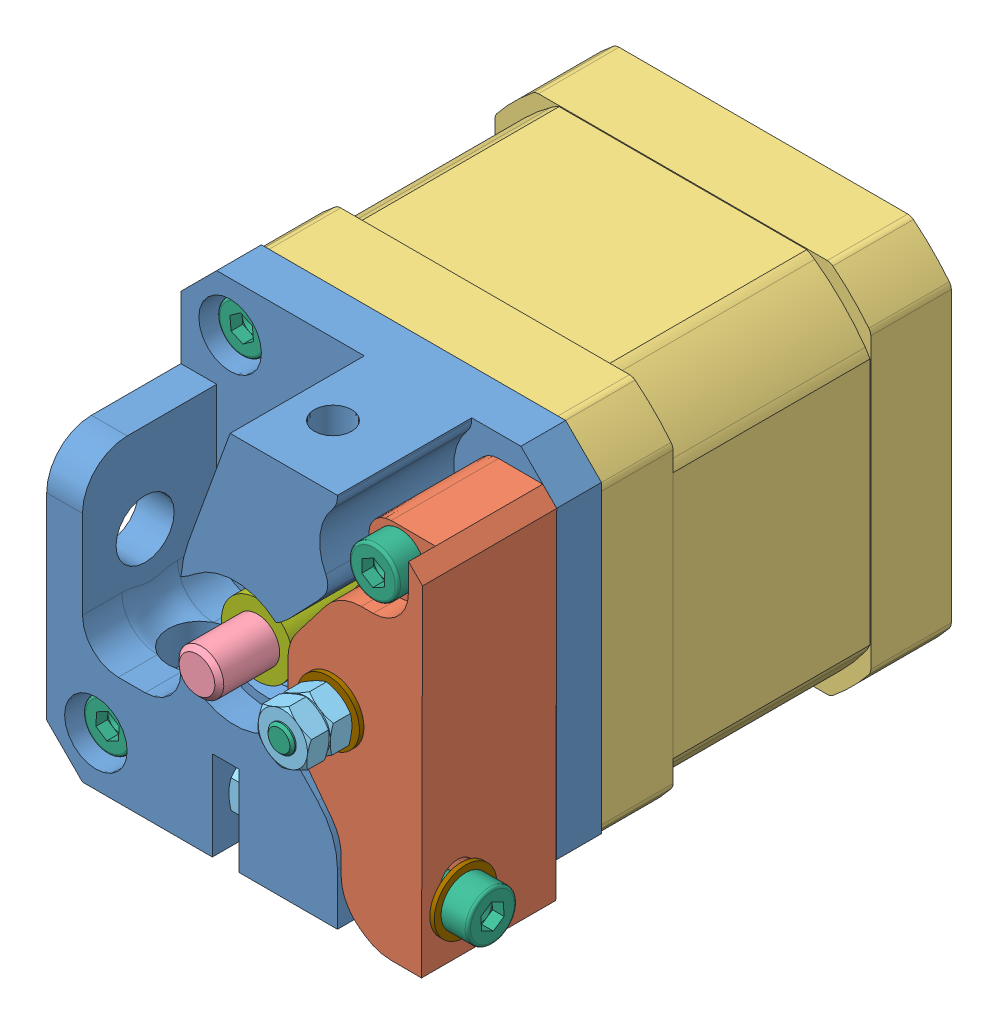
SolidWorks assembly ExtruderDD1, configuration Default. Lengths in mm.
Overall size (45.82 42.02 65.09).
19 component instances, 9 part files, 27 mates.
Components (placement in the parent):
- DD-1 extruder-1: DD-1 extruder [Default] at origin size (42 42 20)
- DD-1 Idler-1: DD-1 Idler [Default] at (21.0104 18.9837 0) x (0.002967 0.999996 0) z (0 0 1) size (39.57 15 15)
- Stepper_motor_NEMA17 39mm-1: Stepper_motor_NEMA17 39mm [Default] at (0 0 -18) x (1 0 0) z (0 -1 0) size (42 63.3 42)
  - Stator-1: Stator [Default] at origin size (42 41.1 42)
  - Rotor-1: Rotor [Default] x (0.508449 0 0.861092) z (-0.861092 0 0.508449) size (21 60.8 21)
- Hex nut-1: Hex nut [M3 Hex Nut] at (-1.8851 -15.1119 -4) x (0 0 1) z (-1 0 0) size (5.5 6.35 2.4)
- Socket head cap screw-1: Socket head cap screw [M3x10] at (-15.5 15.5 -16.3) x (0 0 -1) z (0.417389 0.908728 0) size (13 5.5 5.5)
- Socket head cap screw-3: Socket head cap screw [M3x25] at (24.8182 -15.1119 -4) x (-1 0 0) z (0 0.898586 -0.438797) size (28 5.5 5.5)
- Socket head cap screw-5: Socket head cap screw [M3x20] at (-15.5 -15.5 -1.3) x (0 0 -1) z (0.998489 -0.054943 0) size (23 5.5 5.5)
- Socket head cap screw-7: Socket head cap screw [M3x20] at (15.5 15.5 0) x (0 0 -1) z (-0.467841 0.883812 0) size (23 5.5 5.5)
- MK8 hobbed gear-1: MK8 hobbed gear [Default] at (0 0 -2.5414) x (0.957517 0.288377 0) z (0 0 1) size (8 8 13)
- 4mm Bearing SKF 624 RS 286-7798-1: 4mm Bearing SKF 624 RS 286-7798 [Default] at (10.954 0.0134 -9.5568) x (0 0 -1) z (0.991845 -0.127452 0) size (5 13 13)
- Socket head cap screw-8: Socket head cap screw [M3x16] at (10.954 0.0134 -13.0115) x (0 0 1) z (-0.999739 -0.022865 0) size (19 5.5 5.5)
- Plain washer-1: Plain washer [M3 plain washer] at (10.954 0.0134 -10.0115) x (0 0 -1) z (0.919176 0.393848 0) size (0.5 7 7)
- Plain washer-2: Plain washer [M3 plain washer] at (10.954 0.0134 -4) x (0 0 1) z (-0.416652 -0.909066 0) size (0.5 7 7)
- Plain washer-4: Plain washer [M3 plain washer] at (10.954 0.0134 0.5) x (0 0 1) z (-0.857912 -0.513797 0) size (0.5 7 7)
- Hex nut-2: Hex nut [M3 Hex Nut] at (10.954 0.0134 5.5618) x (0.990359 -0.138525 0) z (0 0 1) size (5.5 6.35 2.4)
- Hex nut-4: Hex nut [M3 Hex Nut] at (10.954 0.0134 2.9968) x (0.998532 -0.054169 0) z (0 0 1) size (5.5 6.35 2.4)
- Plain washer-6: Plain washer [M3 plain washer] at (21.8182 -15.1119 -4) x (1 0 0) z (0 -0.909066 0.416652) size (0.5 7 7)
Mates (geometry in assembly coordinates):
- Coincident1: coincident anti-aligned: plane of DD-1 extruder-1 through (0 0 -15) normal (0 0 1); plane of DD-1 Idler-1 through (21.0104 18.9837 -15) normal (0 0 -1)
- Concentric1: concentric anti-aligned: cylinder of DD-1 extruder-1 through (15.5 15.5 -15) axis (0 0 -1) radius 1.75; cylinder of DD-1 Idler-1 through (15.5 15.5 -15) axis (0 0 1) radius 1.3432
- Coincident2: coincident anti-aligned: plane of DD-1 extruder-1 through (0 0 -20) normal (0 0 -1); plane of Stepper_motor_NEMA17 39mm-1/Stator-1 through (11 0 -20) normal (0 0 1)
- Concentric3: concentric anti-aligned: cylinder of DD-1 extruder-1 through (-15.5 15.5 -15) axis (0 0 -1) radius 1.75; cylinder of Stepper_motor_NEMA17 39mm-1/Stator-1 through (-15.5 15.5 -26) axis (0 0 1) radius 1.25
- Concentric4: concentric anti-aligned: cylinder of DD-1 extruder-1 through (15.5 -15.5 -15) axis (0 0 -1) radius 1.75; cylinder of Stepper_motor_NEMA17 39mm-1/Stator-1 through (15.5 -15.5 -26) axis (0 0 1) radius 1.25
- Concentric5: concentric anti-aligned: cylinder of DD-1 extruder-1 through (11.5 -15.1119 -4) axis (1 0 0) radius 1.5; cylinder of Hex nut-1 through (0.5149 -15.1119 -4) axis (-1 0 0) radius 1.25
- Coincident3: coincident anti-aligned: plane of DD-1 extruder-1 through (0.5149 -11 0) normal (-1 0 0); plane of Hex nut-1 through (0.5149 -11.9365 -4) normal (1 0 0)
- Concentric6: concentric anti-aligned: cylinder of DD-1 extruder-1 through (-15.5 -15.5 -15) axis (0 0 -1) radius 1.75; cylinder of Socket head cap screw-5 through (-15.5 -15.5 30.45) axis (0 0 1) radius 1.5
- Coincident4: coincident anti-aligned: plane of DD-1 extruder-1 through (-15.5 -15.5 -4.3) normal (0 0 1); plane of Socket head cap screw-5 through (-15.3489 -12.7542 -4.3) normal (0 0 -1)
- Concentric7: concentric anti-aligned: cylinder of DD-1 extruder-1 through (-15.5 15.5 -15) axis (0 0 -1) radius 1.75; cylinder of Socket head cap screw-1 through (-15.5 15.5 15.45) axis (0 0 1) radius 1.5
- Coincident5: coincident anti-aligned: plane of DD-1 extruder-1 through (-15.5 15.5 -19.3) normal (0 0 1); plane of Socket head cap screw-1 through (-17.999 16.6478 -19.3) normal (0 0 -1)
- Concentric8: concentric aligned: cylinder of DD-1 Idler-1 through (15.5 15.5 -15) axis (0 0 1) radius 1.3432; cylinder of Socket head cap screw-7 through (15.5 15.5 31.75) axis (0 0 1) radius 1.5
- Coincident6: coincident anti-aligned: plane of DD-1 Idler-1 through (15.5 15.5 -3) normal (0 0 1); plane of Socket head cap screw-7 through (13.0695 14.2134 -3) normal (0 0 -1)
- Concentric9: concentric aligned: cylinder of DD-1 extruder-1 through (11.5 -15.1119 -4) axis (1 0 0) radius 1.5; cylinder of Socket head cap screw-3 through (56.5682 -15.1119 -4) axis (1 0 0) radius 1.5
- Concentric10: concentric aligned: cylinder of Stepper_motor_NEMA17 39mm-1/Rotor-1 through (0 0 4.2) axis (0 0 1) radius 2.5; cylinder of MK8 hobbed gear-1 through (0 0 -15.5414) axis (0 0 1) radius 2.5
- Concentric11: concentric anti-aligned: cylinder of DD-1 Idler-1 through (10.954 0.0134 -15) axis (0 0 1) radius 2; cylinder of 4mm Bearing SKF 624 RS 286-7798-1 through (10.954 0.0134 -9.5568) axis (0 0 -1) radius 2
- Concentric12: concentric aligned: cylinder of 4mm Bearing SKF 624 RS 286-7798-1 through (10.954 0.0134 -9.5568) axis (0 0 -1) radius 2; cylinder of Socket head cap screw-8 through (10.954 0.0134 -44.7615) axis (0 0 -1) radius 1.5
- Concentric13: concentric anti-aligned: cylinder of Socket head cap screw-8 through (10.954 0.0134 -44.7615) axis (0 0 -1) radius 1.5; cylinder of Plain washer-1 through (10.954 0.0134 24.9135) axis (0 0 1) radius 1.6
- Coincident9: coincident anti-aligned: plane of Socket head cap screw-8 through (10.8911 2.7627 -10.0115) normal (0 0 1); plane of Plain washer-1 through (10.3239 1.4841 -10.0115) normal (0 0 -1)
- Concentric14: concentric aligned: cylinder of Socket head cap screw-8 through (10.954 0.0134 -44.7615) axis (0 0 -1) radius 1.5; cylinder of Plain washer-2 through (10.954 0.0134 -38.925) axis (0 0 -1) radius 1.6
- Coincident10: coincident anti-aligned: plane of DD-1 Idler-1 through (10.954 0.0134 -4) normal (0 0 -1); plane of Plain washer-2 through (9.4995 0.6801 -4) normal (0 0 1)
- Coincident11: coincident anti-aligned: plane of DD-1 Idler-1 through (21.0104 18.9837 0) normal (0 0 1); plane of Plain washer-4 through (9.1557 3.0161 0) normal (0 0 -1)
- Concentric15: concentric aligned: cylinder of Socket head cap screw-8 through (10.954 0.0134 -44.7615) axis (0 0 -1) radius 1.5; cylinder of Plain washer-4 through (10.954 0.0134 -34.425) axis (0 0 -1) radius 1.6
- Concentric16: concentric anti-aligned: cylinder of Socket head cap screw-8 through (10.954 0.0134 -44.7615) axis (0 0 -1) radius 1.5; cylinder of Hex nut-2 through (10.954 0.0134 3.1618) axis (0 0 1) radius 1.25
- Concentric17: concentric anti-aligned: cylinder of Socket head cap screw-8 through (10.954 0.0134 -44.7615) axis (0 0 -1) radius 1.5; cylinder of Hex nut-4 through (10.954 0.0134 0.5968) axis (0 0 1) radius 1.25
- Concentric18: concentric anti-aligned: cylinder of Socket head cap screw-3 through (56.5682 -15.1119 -4) axis (1 0 0) radius 1.5; cylinder of Plain washer-6 through (-13.1068 -15.1119 -4) axis (-1 0 0) radius 1.6
- Coincident12: coincident anti-aligned: plane of Socket head cap screw-3 through (21.8182 -13.9052 -1.5289) normal (-1 0 0); plane of Plain washer-6 through (21.8182 -14.4453 -2.5455) normal (1 0 0)
